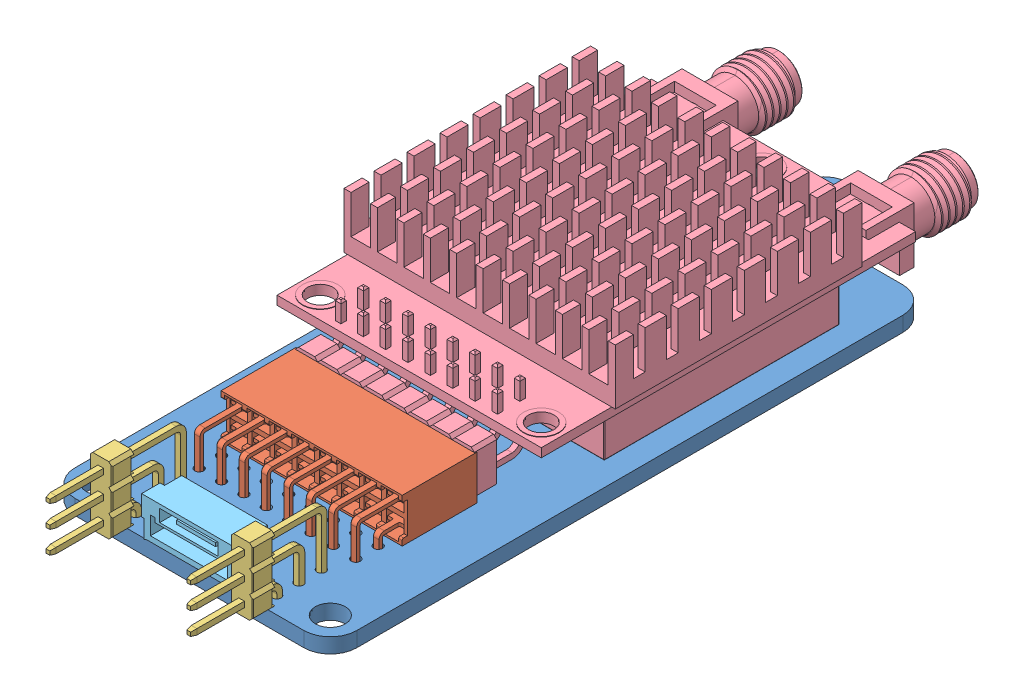
SolidWorks assembly RFD900x Carrier Assembly, configuration Default. Lengths in mm.
Overall size (32 16 85.06).
6 component instances, 5 part files, 12 mates.
Components (placement in the parent):
- RFD900x Carrier Board PCB-1: RFD900x Carrier Board PCB [Default] at (5.5031 30.7417 75.1429) size (32 1.7 75)
- A-BL254-DA-G16D-1: A-BL254-DA-G16D [Default] at (21.5021 34.9417 61.2686) x (1 0 0) z (0 1 0) size (20.57 12.6 8.2)
- Pins header - 2.54 Horizontal 1x3-1: Pins header - 2.54 Horizontal 1x3 [Défaut] at (13.5235 33.7117 75.984) size (2.54 9.62 15.4)
- Pins header - 2.54 Horizontal 1x3-2: Pins header - 2.54 Horizontal 1x3 [Défaut] at (29.5083 33.7117 75.9791) size (2.54 9.62 15.4)
- RFD900X-1: RFD900X [Default] at (21.5031 37.9417 28.9429) x (-1 0 0) z (0 -1 0) size (30.8 60.8 12.8)
- SM06B-GHS-TB-RASM-1: SM06B-GHS-TB-RASM [Default] at (26.8236 32.4417 71.0929) size (10.75 4.35 4.85)
Mates (geometry in assembly coordinates):
- Coincident1: coincident anti-aligned: plane of RFD900x Carrier Board PCB-1 through (21.5031 32.4417 3.1429) normal (0 1 0); plane of A-BL254-DA-G16D-1 through (31.7871 32.4417 57.0186) normal (0 -1 0)
- Coincident2: coincident anti-aligned: plane of RFD900x Carrier Board PCB-1 through (21.5031 32.4417 3.1429) normal (0 1 0); plane of Pins header - 2.54 Horizontal 1x3-2 through (29.5083 32.4417 77.2291) normal (0 -1 0)
- Coincident3: coincident anti-aligned: plane of RFD900x Carrier Board PCB-1 through (21.5031 32.4417 3.1429) normal (0 1 0); plane of Pins header - 2.54 Horizontal 1x3-1 through (13.5235 32.4417 77.234) normal (0 -1 0)
- Lock1: lock: 
- Lock2: lock: 
- Lock3: lock: 
- Coincident4: coincident anti-aligned: plane of RFD900x Carrier Board PCB-1 through (21.5031 32.4417 3.1429) normal (0 1 0); plane of RFD900X-1 through (21.5031 32.4417 28.9429) normal (0 -1 0)
- Concentric1: concentric aligned: cylinder of RFD900x Carrier Board PCB-1 through (21.5031 32.4417 10.1429) axis (0 -1 0) radius 2.25; cylinder of RFD900X-1 through (21.5031 38.9417 10.1429) axis (0 -1 0) radius 1.45
- Parallel1: parallel aligned: plane of A-BL254-DA-G16D-1 through (11.2171 34.9417 57.092) normal (-1 0 0); plane of RFD900X-1 through (11.3676 35.2719 52.9717) normal (-1 0 0)
- Coincident5: coincident aligned: plane of RFD900x Carrier Board PCB-1 through (8.5031 32.4417 75.1429) normal (0 0 1); plane of SM06B-GHS-TB-RASM-1 through (16.0736 32.3417 75.1429) normal (0 0 1)
- Coincident6: coincident anti-aligned: plane of RFD900x Carrier Board PCB-1 through (21.5031 32.4417 3.1429) normal (0 1 0); plane of SM06B-GHS-TB-RASM-1 through (26.8236 32.4417 71.7429) normal (0 -1 0)
- Lock4: lock: 
